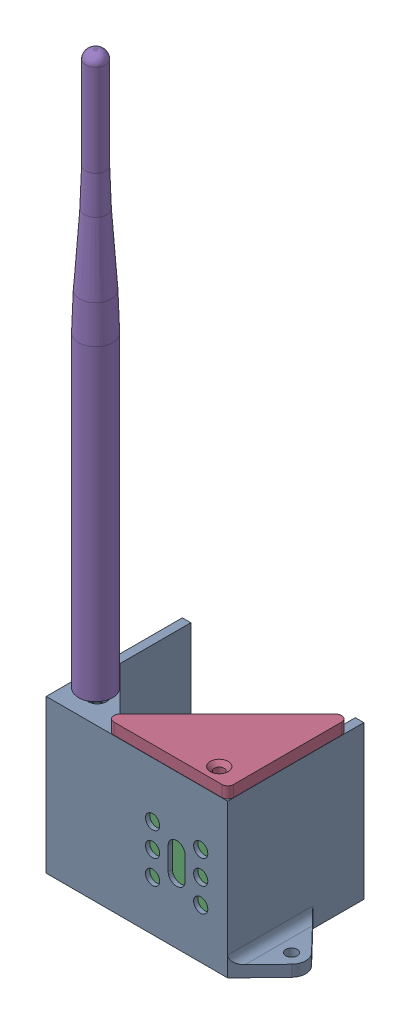
SolidWorks assembly R7_GS_1400_LORA, configuration Domyślna. Lengths in mm.
Overall size (89 251.86 48).
5 component instances, 5 part files, 0 mates.
Components (placement in the parent):
- R7_GS_1410_CASE_BOTTOM-1: R7_GS_1410_CASE_BOTTOM [Domyślna] at (-3.5099 -22.9886 0) size (89 54 48)
- R7_GS_1420_LORA_BOARD-1: R7_GS_1420_LORA_BOARD [Domyślna] at (-5.4335 -18.1224 -0.2235) x (-1 0 0) z (0 0 -1) size (50 20.5 38.5)
- R7_GS_1430_GNSS-1: R7_GS_1430_GNSS [Domyślna] at (10.466 3.0326 22.4228) x (-1 0 0) z (0 0 -1) size (25 30 8)
- R7_GS_1440_CASE_TOP-1: R7_GS_1440_CASE_TOP [Domyślna] at (6.3092 31.0944 1.1774) x (0 0 -1) z (1 0 0) size (42.17 36 42.17)
- R7_GS_1450_ANTENNA_915-1: R7_GS_1450_ANTENNA_915 [Domyślna] at (-26.5351 33.8758 15.5496) size (12 195 12)
